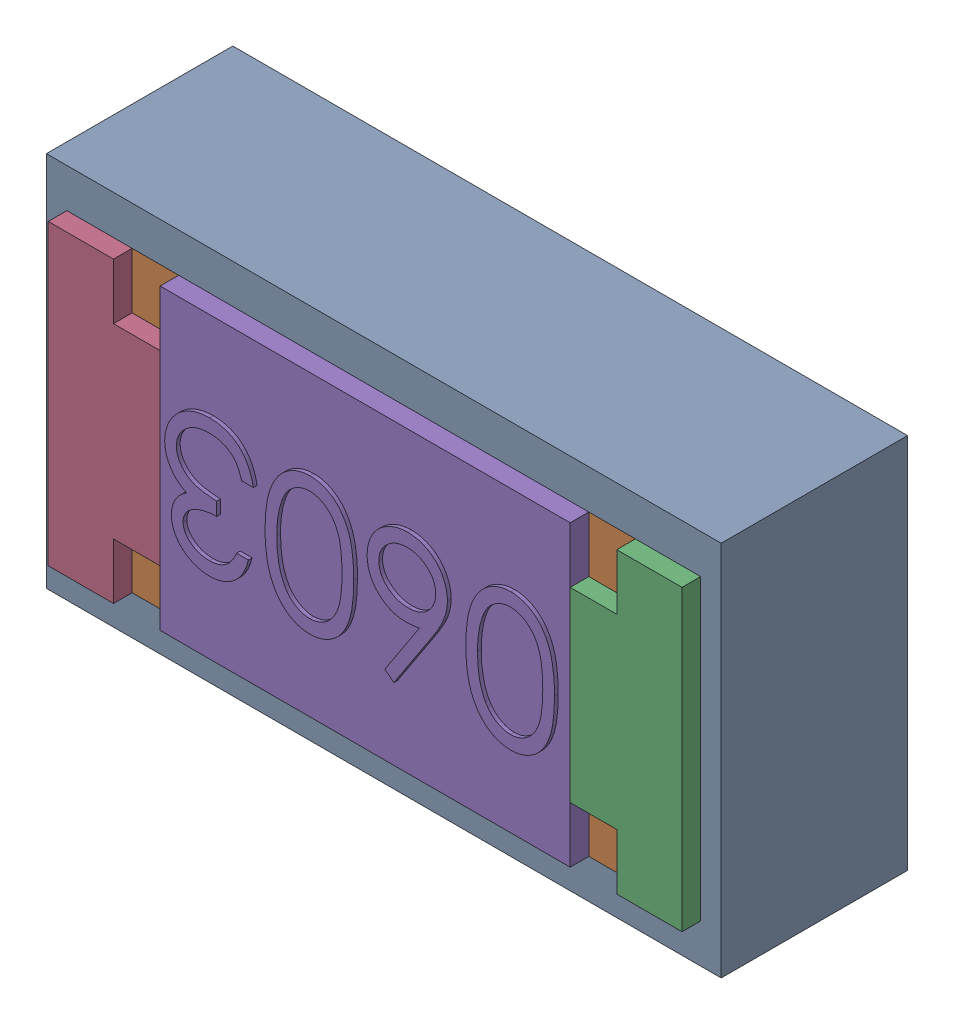
SolidWorks assembly SB3, configuration Default. Lengths in mm.
Overall size (1.81 1.01 0.56).
3 component instances, 2 part files, 0 mates.
Components (placement in the parent):
- 1088884160-1: 1088884160 [Default] at (8.175 24.825 0) size (1.81 1.01 0.5)
  - Extruded-27-1: Extruded-27 [Default] at origin size (1.81 1.01 0.5)
- R0603-1: R0603 [Default] at (8.1749 24.8249 0) x (-1 0 0) z (0 1 0) size (1.7 0.56 0.8)
